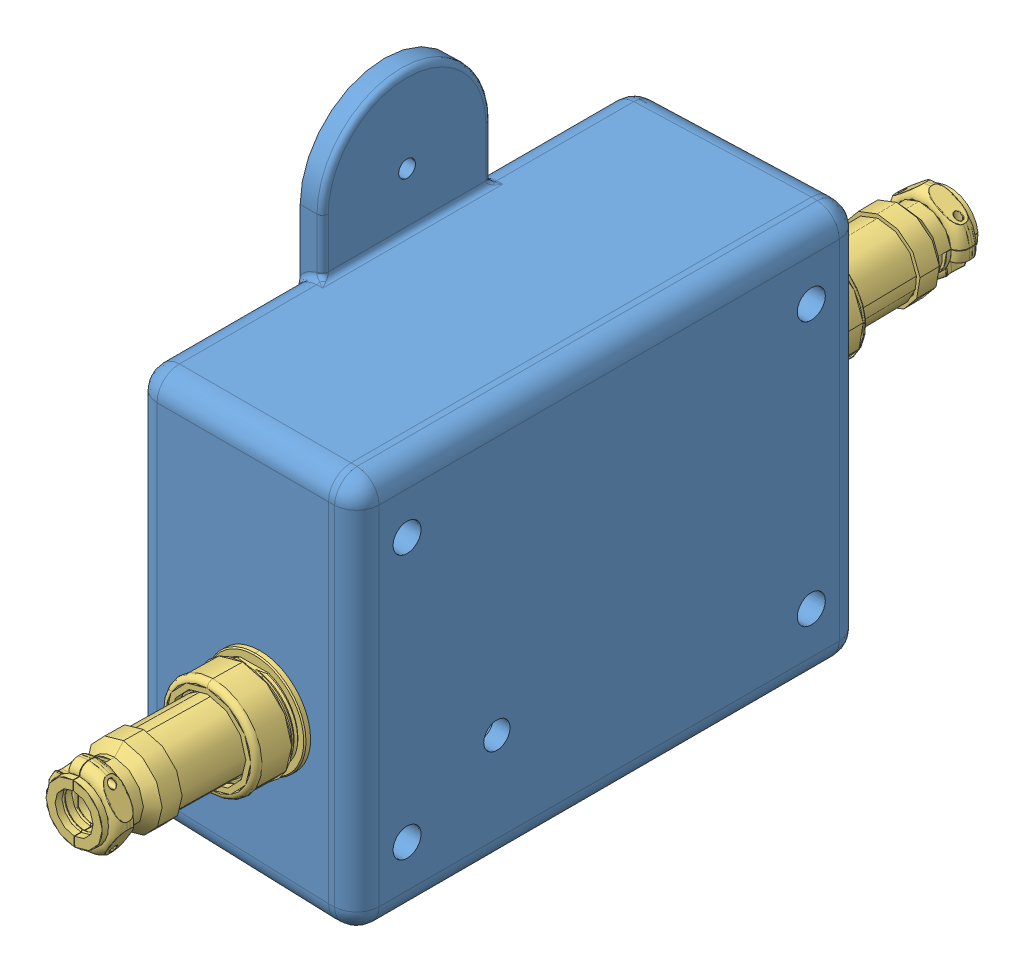
SolidWorks assembly Module_Assem, configuration Default. Lengths in mm.
Overall size (40 118.85 101.97).
4 component instances, 3 part files, 4 mates.
Components (placement in the parent):
- Module-1: Module [Default] at (58.1482 61.5557 111.8773) size (40 118.85 90)
- Sensor_PCB.step-1: Sensor_PCB.step [Default] at (32.5857 18.0107 158.8326) x (0 -0.001154 -0.999999) z (1 0 0) size (46.6 38.61 15.7)
- GX16-4P v2.step-1: GX16-4P v2.step [Default] at (45.3324 54.2793 189.3585) x (0.017452 0 -0.999848) z (-0.023825 0.999716 -0.000416) size (47.5 21.45 18.91)
- GX16-4P v2.step-2: GX16-4P v2.step [Default] at (46.1678 68.8229 34.3814) x (0.017452 0 0.999848) z (0.995324 0.095017 -0.017373) size (47.5 21.45 18.91)
Mates (geometry in assembly coordinates):
- Coincident1: coincident anti-aligned: plane of Module-1 through (30.8942 45.1107 91.2373) normal (1 0 0); plane of Sensor_PCB.step-1 through (30.8942 61.6447 111.9847) normal (-1 0 0)
- Coincident2: coincident aligned: circle of Module-1; circle of Sensor_PCB.step-1
- Coincident3: coincident anti-aligned: plane of Module-1 through (58.2006 96.5557 69.8768) normal (0.017452 0 0.999848); plane of GX16-4P v2.step-2 through (46.7908 68.8229 70.076) normal (-0.017452 0 -0.999848)
- Coincident5: coincident anti-aligned: plane of Module-1 through (58.2006 96.5557 153.8777) normal (0.017452 0 -0.999848); plane of GX16-4P v2.step-1 through (45.9554 54.2793 153.664) normal (-0.017452 0 0.999848)
